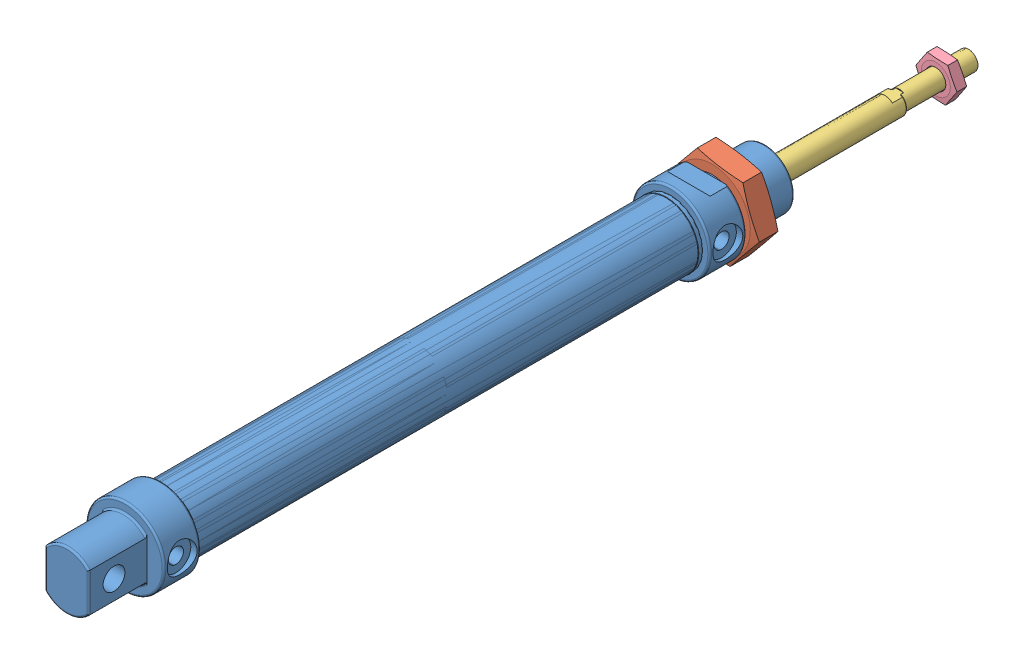
SolidWorks assembly gg16 X 100 Cylinder, configuration Default. Lengths in mm.
Overall size (28.61 25.8 247.92).
4 component instances, 4 part files, 0 mates.
Components (placement in the parent):
- 16 X 100 Cylinder bore-1: 16 X 100 Cylinder bore [Default] at origin size (21.5 21.5 192)
- Nut 16-1: Nut 16 [Default] at (0 0 -84.4173) x (0.986962 -0.160953 0) z (-0.160953 -0.986962 0) size (25.4 6 22)
- Rod-1: Rod [Default] at (0 0 13.0842) x (0.024302 0.999705 0) z (-0.999705 0.024302 0) size (6.2 165 6.2)
- Nut 5-1: Nut 5 [Default] at (0 0 -144.4158) x (0.997949 -0.06401 0) z (0.06401 0.997949 0) size (11.32 3 9.8)
